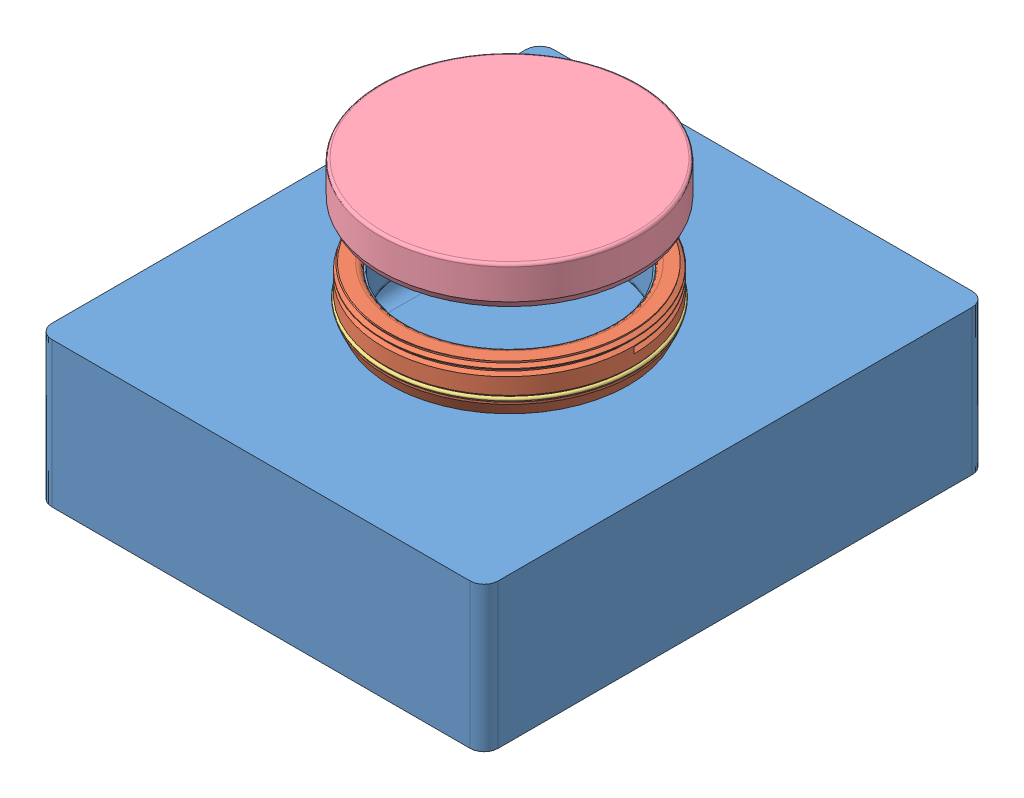
SolidWorks assembly Model Sailboat external enclosure Assembly 5.11.18, configuration Default. Lengths in mm.
Overall size (203.2 128.65 228.6).
4 component instances, 4 part files, 8 mates.
Components (placement in the parent):
- Model Sailboat internal enclosure-1: Model Sailboat internal enclosure [Default] at (175.6992 196.6233 340.5165) size (203.2 85.09 228.6)
- External enclosure fitting 5.11.18-1: External enclosure fitting 5.11.18 [Default] at (175.6992 256.3133 340.5165) x (1 0 0) z (0 1 0) size (114.76 114.46 24.02)
- Enclosure O-Ring-1: Enclosure O-Ring [Default] at (121.2364 260.7519 325.8104) x (0.582036 0 0.813163) z (-0.813163 0 0.582036) size (114.62 64.47 114.62)
- External enclosure cap 5.11.18-1: External enclosure cap 5.11.18 [Default] at (121.2364 301.1473 325.8104) x (0.692835 0 -0.721096) z (0.721096 0 0.692835) size (118.11 17.78 118.11)
Mates (geometry in assembly coordinates):
- InPlace1: in place: plane of ? through (134.6606 136.9308 198.0126) normal (0 1 0); plane of ? through (0 136.9308 0) normal (0 1 0); moOrthogonalPlaneRef_w of ? through (134.6606 136.9308 198.0126) normal (0 1 0); plane of ? through (0 136.9308 0) normal (0 0 -1); plane of ? through (134.6606 136.9308 198.0126) normal (0 1 0); plane of ? through (0 136.9308 0) normal (1 0 0); plane of Model Sailboat internal enclosure-1 through (175.6992 256.3133 340.5165) normal (0 1 0); unknown of External enclosure fitting 5.11.18-1
- Coincident1: coincident aligned: plane of Model Sailboat internal enclosure-1; plane of External enclosure fitting 5.11.18-1
- Coincident2: coincident aligned: moOrthogonalPlaneRef_w of Model Sailboat internal enclosure-1 through (175.6992 256.3133 340.5165) normal (0 0 -1); plane of External enclosure fitting 5.11.18-1 through (175.6992 256.3133 340.5165) normal (0 0 -1)
- Coincident3: coincident anti-aligned: moOrthogonalPlaneRef_w of Model Sailboat internal enclosure-1 through (175.6992 256.3133 340.5165) normal (-1 0 0); plane of External enclosure fitting 5.11.18-1 through (175.6992 256.3133 340.5165) normal (1 0 0)
- Lock1: lock: unknown of Model Sailboat internal enclosure-1
- LimitDistance1: limit distance = 44.834 mm anti-aligned: plane of External enclosure cap 5.11.18-1 through (121.2364 301.1473 325.8104) normal (0 -1 0); plane of Model Sailboat internal enclosure-1 through (175.6992 256.3133 340.5165) normal (0 1 0)
- Concentric3: concentric anti-aligned: cylinder of External enclosure fitting 5.11.18-1 through (121.2364 265.3303 325.8104) axis (0 -1 0) radius 55.3339; line of Enclosure O-Ring-1 through (121.2364 231.6903 325.8104) axis (0 1 0)
- Concentric4: concentric aligned: line of Enclosure O-Ring-1 through (121.2364 231.6903 325.8104) axis (0 1 0); circle of External enclosure cap 5.11.18-1
